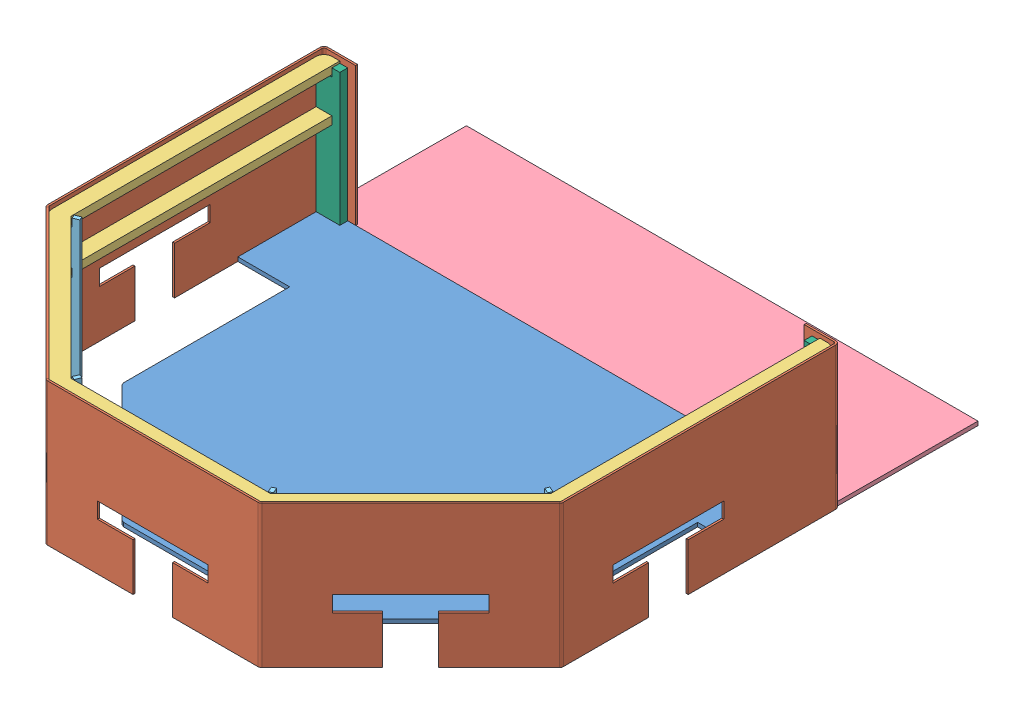
SolidWorks assembly STATION, CHASSIS, TOP ASSY, configuration Default. Lengths in mm.
Overall size (414.01 114.82 457.19).
12 component instances, 6 part files, 27 mates.
Components (placement in the parent):
- CHARGING, PLATE, Base-1: CHARGING, PLATE, Base [Default] at origin size (410.84 3.17 299.65)
- CHARGING, PLATE, Outer Shell-1: CHARGING, PLATE, Outer Shell [Default] at origin size (414.01 114.3 344.48)
- CHARGING, PLATE, Station Backstop-1: CHARGING, PLATE, Station Backstop [Default] at (0 69.85 0) size (410.84 6.35 341.3)
- CHARGING, PLATE, Base-2: CHARGING, PLATE, Base [Top] at (0 111.125 0) size (410.84 3.17 341.3) (hidden)
- STATION, CHASSIS, REAR PLATE-1: STATION, CHASSIS, REAR PLATE [Default] at (0 1.3254 -193.0289) x (1 0 0) z (0 0.999989 -0.004586) size (410.72 114.3 3.17)
- CHARGING, PLATE, Station Backstop-2: CHARGING, PLATE, Station Backstop [Default] at (0 104.775 0) size (410.84 6.35 341.3)
- STATION, CHASSIS, Vertical Struts-1: STATION, CHASSIS, Vertical Struts [Default] at (81.1901 55.5625 196.0102) x (0.92388 0 -0.382683) z (0.382683 0 0.92388) size (3.17 111.12 19.05)
- STATION, CHASSIS, Vertical Struts-2: STATION, CHASSIS, Vertical Struts [Default] at (-81.1901 55.5625 196.0102) x (0.92388 0 0.382683) z (-0.382683 0 0.92388) size (3.17 111.12 19.05)
- STATION, CHASSIS, Vertical Struts-3: STATION, CHASSIS, Vertical Struts [Default] at (-196.0102 55.5625 81.1901) x (0.382683 0 0.92388) z (-0.92388 0 0.382683) size (3.17 111.12 19.05)
- STATION, CHASSIS, Vertical Struts-4: STATION, CHASSIS, Vertical Struts [Default] at (196.0102 55.5625 81.1901) x (0.382683 0 -0.92388) z (0.92388 0 0.382683) size (3.17 111.12 19.05)
- STATION, CHASSIS, Vertical Struts, Rear-1: STATION, CHASSIS, Vertical Struts, Rear [Default] at (195.8927 55.5625 -132.7118) x (0 0 -1) z (1 0 0) size (6.35 107.95 19.05)
- STATION, CHASSIS, Vertical Struts, Rear-2: STATION, CHASSIS, Vertical Struts, Rear [Default] at (-195.8927 55.5625 -132.7118) x (0 0 1) z (-1 0 0) size (6.35 107.95 19.05)
Mates (geometry in assembly coordinates):
- Coincident1: coincident aligned: plane of CHARGING, PLATE, Base-1 through (0 0 0) normal (0 0 1); plane of CHARGING, PLATE, Outer Shell-1 through (0 0 0) normal (0 0 1)
- Coincident2: coincident: plane of CHARGING, PLATE, Base-1 through (0 0 0) normal (1 0 0); point of CHARGING, PLATE, Outer Shell-1
- Coincident3: coincident aligned: plane of CHARGING, PLATE, Base-1 through (0 0 0) normal (0 1 0); plane of CHARGING, PLATE, Outer Shell-1 through (0 0 0) normal (0 1 0)
- Coincident6: coincident aligned: plane of CHARGING, PLATE, Base-1 through (0 0 0) normal (0 0 1); plane of CHARGING, PLATE, Station Backstop-1 through (0 69.85 0) normal (0 0 1)
- Coincident7: coincident aligned: plane of CHARGING, PLATE, Base-1 through (0 0 0) normal (1 0 0); plane of CHARGING, PLATE, Station Backstop-1 through (0 69.85 0) normal (1 0 0)
- Distance1: distance = 69.85 mm aligned: plane of CHARGING, PLATE, Base-1 through (-205.4177 0 -135.8868) normal (0 -1 0); plane of CHARGING, PLATE, Station Backstop-1 through (199.0677 69.85 -129.5368) normal (0 -1 0)
- Coincident8: coincident aligned: plane of CHARGING, PLATE, Base-1 through (0 0 0) normal (0 0 1); plane of assembly through (0 0 0) normal (0 0 1)
- Coincident9: coincident aligned: plane of CHARGING, PLATE, Base-1 through (0 0 0) normal (0 1 0); plane of assembly through (0 0 0) normal (0 1 0)
- Coincident10: coincident aligned: plane of CHARGING, PLATE, Base-1 through (0 0 0) normal (1 0 0); plane of assembly through (0 0 0) normal (1 0 0)
- Coincident11: coincident aligned: plane of CHARGING, PLATE, Base-2 through (0 111.125 0) normal (1 0 0); plane of assembly through (0 0 0) normal (1 0 0)
- Coincident12: coincident aligned: plane of CHARGING, PLATE, Outer Shell-1 through (-203.8175 114.3 -137.4743) normal (0 1 0); plane of CHARGING, PLATE, Base-2 through (-205.4177 114.3 -135.8868) normal (0 1 0)
- Coincident13: coincident aligned: plane of CHARGING, PLATE, Base-2 through (0 111.125 0) normal (0 0 1); plane of assembly through (0 0 0) normal (0 0 1)
- Coincident15: coincident aligned: plane of STATION, CHASSIS, REAR PLATE-1; plane of assembly through (0 0 0) normal (1 0 0)
- Coincident25: coincident anti-aligned: line of CHARGING, PLATE, Base-1 through (205.4177 3.175 -135.8868) axis (-1 0 0); line of STATION, CHASSIS, REAR PLATE-1 through (-205.359 3.175 -135.8868) axis (1 0 0)
- Distance2: distance = 3.175 mm aligned: plane of CHARGING, PLATE, Station Backstop-2 through (199.0677 111.125 -129.5368) normal (0 1 0); plane of CHARGING, PLATE, Outer Shell-1 through (-86.678 114.3 206.0715) normal (0 1 0)
- Coincident28: coincident aligned: plane of CHARGING, PLATE, Station Backstop-1 through (0 69.85 0) normal (0 0 1); plane of CHARGING, PLATE, Station Backstop-2 through (0 104.775 0) normal (0 0 1)
- Coincident29: coincident aligned: plane of CHARGING, PLATE, Station Backstop-1 through (0 69.85 0) normal (1 0 0); plane of CHARGING, PLATE, Station Backstop-2 through (0 104.775 0) normal (1 0 0)
- Angle1: planar angle = 0.392699 rad aligned: plane of STATION, CHASSIS, Vertical Struts-1 through (81.1901 55.5625 196.0102) normal (0.92388 0 -0.382683); plane of assembly through (0 0 0) normal (1 0 0)
- Coincident30: coincident anti-aligned: plane of CHARGING, PLATE, Station Backstop-2 through (199.0677 104.775 -129.5368) normal (0 -1 0); plane of STATION, CHASSIS, Vertical Struts-1 through (83.3685 104.775 205.4177) normal (0 1 0)
- Coincident31: coincident: plane of CHARGING, PLATE, Outer Shell-1 through (85.0868 114.3 205.4177) normal (-0.707107 0 -0.707107); line of STATION, CHASSIS, Vertical Struts-1 through (86.3018 69.85 204.2027) axis (0 -1 0)
- Coincident32: coincident: plane of CHARGING, PLATE, Outer Shell-1 through (-85.0868 114.3 205.4177) normal (0 0 -1); line of STATION, CHASSIS, Vertical Struts-1 through (83.3685 69.85 205.4177) axis (0 -1 0)
- Coincident35: coincident anti-aligned: plane of CHARGING, PLATE, Outer Shell-1 through (205.4177 114.3 85.0868) normal (-1 0 0); plane of STATION, CHASSIS, Vertical Struts, Rear-1 through (205.4177 109.5375 -135.8868) normal (1 0 0)
- Coincident36: coincident anti-aligned: plane of CHARGING, PLATE, Station Backstop-1 through (199.0677 76.2 -129.5368) normal (0 1 0); plane of STATION, CHASSIS, Vertical Struts, Rear-1 through (205.4177 76.2 -129.5368) normal (0 -1 0)
- Coincident38: coincident anti-aligned: plane of CHARGING, PLATE, Outer Shell-1 through (205.4177 114.3 -135.8868) normal (0 0 1); plane of STATION, CHASSIS, Vertical Struts, Rear-1 through (186.3677 1.5875 -135.8868) normal (0 0 -1)
- Coincident39: coincident anti-aligned: plane of CHARGING, PLATE, Outer Shell-1 through (-180.0177 114.3 -135.8868) normal (0 0 1); plane of STATION, CHASSIS, Vertical Struts, Rear-2 through (-186.3677 1.5875 -135.8868) normal (0 0 -1)
- Coincident40: coincident anti-aligned: plane of CHARGING, PLATE, Station Backstop-1 through (199.0677 76.2 -129.5368) normal (0 1 0); plane of STATION, CHASSIS, Vertical Struts, Rear-2 through (-205.4177 76.2 -135.8868) normal (0 -1 0)
- Coincident41: coincident anti-aligned: plane of ? through (-205.4177 114.3 -135.8868) normal (1 0 0); plane of STATION, CHASSIS, Vertical Struts, Rear-2 through (-205.4177 109.5375 -129.5368) normal (-1 0 0)
